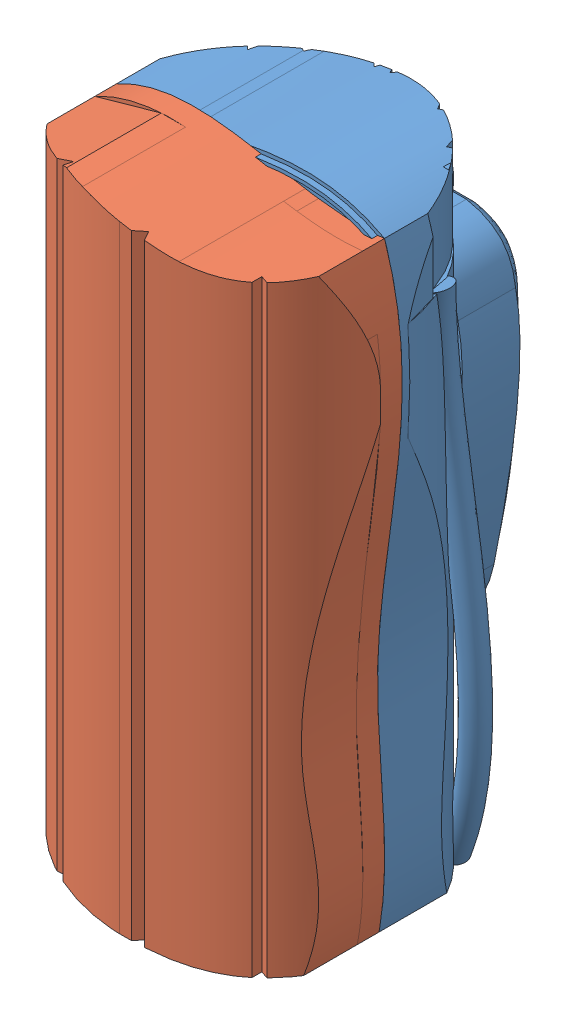
SolidWorks assembly Assem1, configuration Default. Lengths in mm.
Overall size (130.26 223.68 105.2).
2 component instances, 2 part files, 2 mates.
Components (placement in the parent):
- front part final-1: front part final [Default] at (41.7881 138.4084 178.977) size (124.77 223.68 67.4)
- back half-2: back half [Default] at (41.7881 138.4084 272.977) x (-1 0 0) z (0 0 -1) size (130.26 219.62 54.77)
Mates (geometry in assembly coordinates):
- Tangent7: tangent: curve of front part final-1; curve of back half-2
- Tangent8: tangent: curve of front part final-1; curve of back half-2
